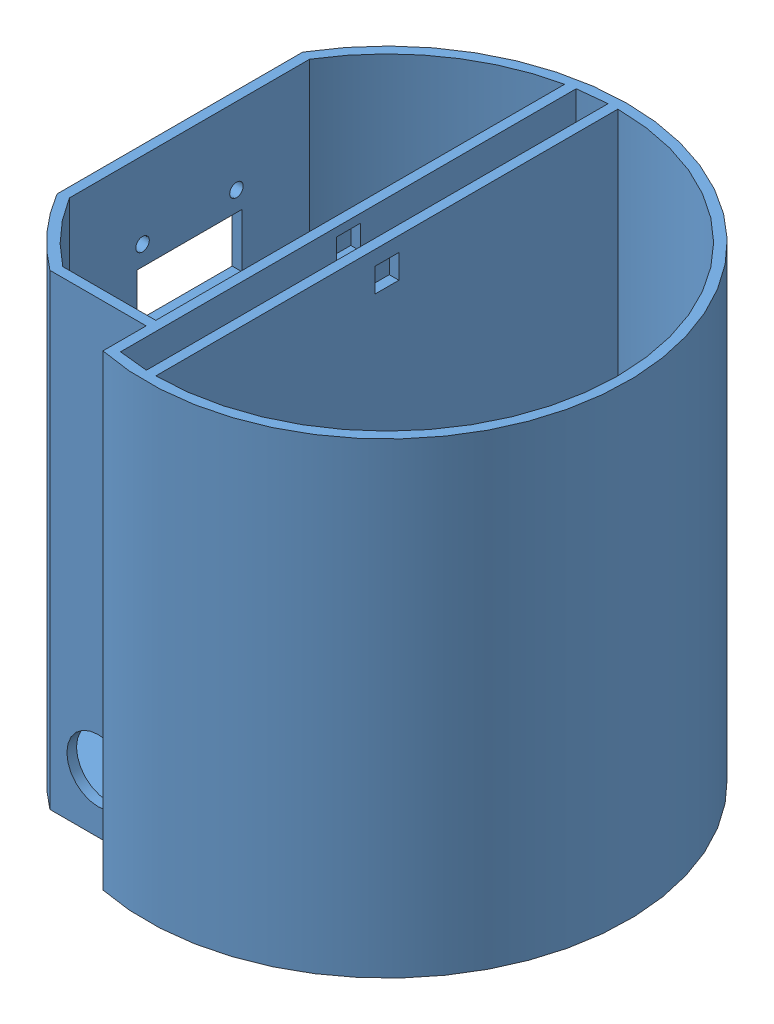
SolidWorks assembly modified_assembly, configuration Default. Lengths in mm.
Overall size (93 97 100).
3 component instances, 3 part files, 2 mates.
Components (placement in the parent):
- Bottom-1: Bottom [Default] at origin size (93 97 100)
- TOP-3: TOP [Default] at (0 97 0) x (0.99999 0 0.004373) z (-0.004373 0 0.99999) (suppressed, hidden)
- inside-2: inside [Default] at (0 86.5444 0) x (0.999898 0 -0.014306) z (0.014306 0 0.999898) (suppressed, hidden)
Mates (geometry in assembly coordinates):
- Concentric1: concentric aligned: cylinder of Bottom-1 through (0 97 0) axis (0 -1 0) radius 48; cylinder of inside-2 through (0 89.5444 0) axis (0 -1 0) radius 48
- Coincident2: coincident aligned: circle of Bottom-1; circle of TOP-3
